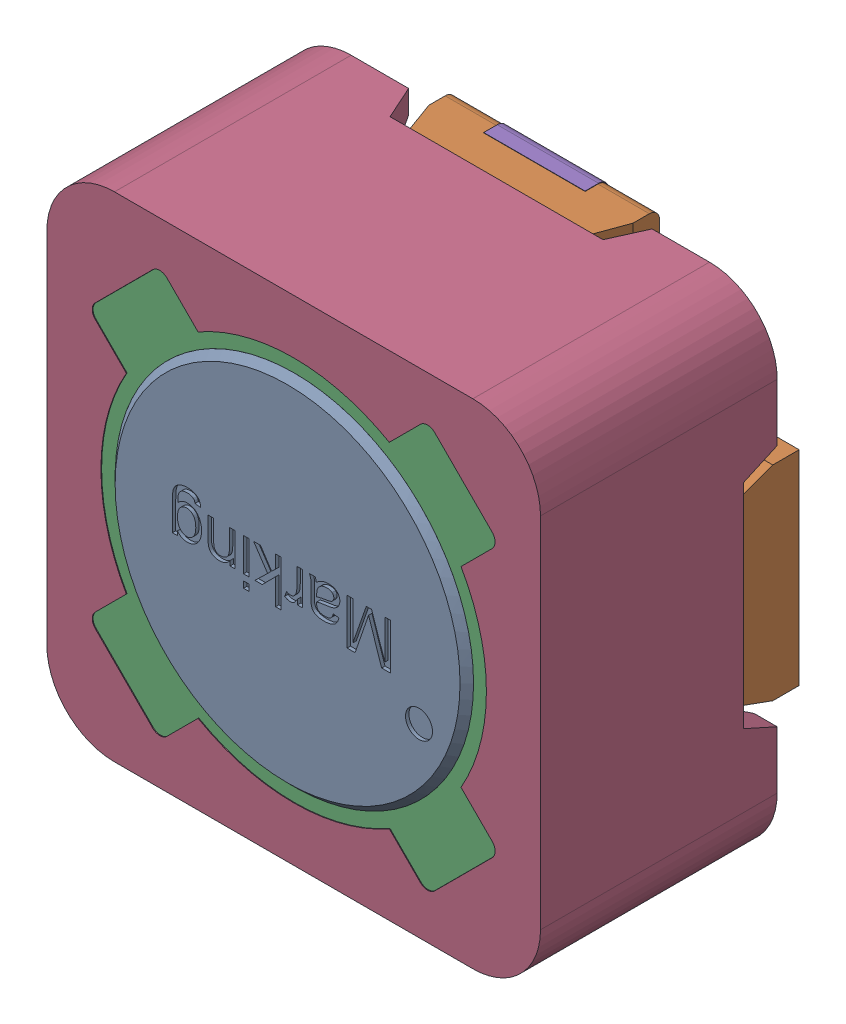
SolidWorks assembly IndPDA_7345, configuration Default. Lengths in mm.
Overall size (7.3 7.3 4).
11 component instances, 7 part files, 0 mates.
Components (placement in the parent):
- Ferrite_5.3x3.6-1: Ferrite_5.3x3.6 [Default] at (0 0 0.15) size (5.3 5.3 3.6)
- Umspritzung_1-1: Umspritzung_1 [Default] at (0 0 0.66) x (1 0 0) z (0 0 -1) size (7.15 7.15 0.9)
- Glue_2-1: Glue_2 [Default] at origin size (5.95 5.95 2.94)
- Ferrite-Ring7.3x3.5x5.7-1: Ferrite-Ring7.3x3.5x5.7 [Default] at (0 0 0.16) size (7.3 7.3 3.5)
- Leadframe-1: Leadframe [Default] at origin size (7.19 7.19 3.21)
  - Leadframe_3-1: Leadframe_3 [Default] at origin size (5.16 2.58 0.5)
  - Leadframe_4-1: Leadframe_4 [Default] at origin size (5.16 2.58 0.5)
  - contact-1: contact [Default] at (-2.3342 -2.3342 -3.3) x (0.5 -0.5 0.707107) z (0.707107 0.707107 0) size (2.16 2.16 0.93)
  - contact-2: contact [Default] at (2.3342 -2.3342 -3.3) x (0.5 0.5 0.707107) z (-0.707107 0.707107 0) size (2.16 2.16 0.93)
  - contact-3: contact [Default] at (2.3342 2.3342 -3.3) x (-0.5 0.5 0.707107) z (-0.707107 -0.707107 0) size (2.16 2.16 0.93)
  - contact-4: contact [Default] at (-2.3342 2.3342 -3.3) x (-0.5 -0.5 0.707107) z (0.707107 -0.707107 0) size (2.16 2.16 0.93)
